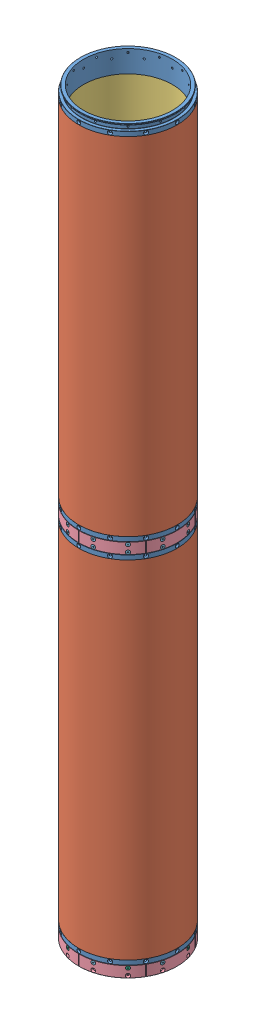
SolidWorks assembly couplingExample, configuration Default. Lengths in mm.
Overall size (235.05 1268.91 235.05).
59 component instances, 6 part files, 14 mates.
Components (placement in the parent):
- module24-1: module24 [Default] at (-49.5864 13.6661 16.8815) size (235.05 629.76 235.05)
  - moduleRing-1: moduleRing [Default] at (25.7042 -360.5051 -16.6209) size (168.91 37.68 168.91)
  - moduleRing-2: moduleRing [Default] at (25.7042 248.3364 -16.6209) x (-1 0 0) z (0 0 1) size (168.91 37.68 168.91)
  - compositeOuterSleeve-1: compositeOuterSleeve [Default] at (25.7042 -353.5986 -16.6209) x (-0.821874 0 -0.569669) z (0.569669 0 -0.821874) size (168.91 595.03 168.91)
  - compositeInnerSleeve-1: compositeInnerSleeve [Default] at (25.7042 -343.4386 -16.6209) x (0.952124 0 0.305713) z (-0.305713 0 0.952124) size (154.43 574.71 154.43)
- module24-2: module24 [Default] at (-40.5031 643.4225 -25.4436) x (0 0 1) z (-1 0 0) size (235.05 629.76 235.05)
  - moduleRing-1: moduleRing [Default] at (25.7042 -360.5051 -16.6209) size (168.91 37.68 168.91)
  - moduleRing-2: moduleRing [Default] at (25.7042 248.3364 -16.6209) x (-1 0 0) z (0 0 1) size (168.91 37.68 168.91)
  - compositeOuterSleeve-1: compositeOuterSleeve [Default] at (25.7042 -353.5986 -16.6209) x (-0.821874 0 -0.569669) z (0.569669 0 -0.821874) size (168.91 595.03 168.91)
  - compositeInnerSleeve-1: compositeInnerSleeve [Default] at (25.7042 -343.4386 -16.6209) x (0.952124 0 0.305713) z (-0.305713 0 0.952124) size (154.43 574.71 154.43)
- clampArc-1: clampArc [Default] at (-23.8822 263.0581 0.2606) x (0.866025 0 -0.500001) z (0.500001 0 0.866025) size (83.87 18.8 15.42)
- clampArc-7: clampArc [Default] at (-23.8822 -366.6983 0.2606) x (0.866025 0 -0.500001) z (0.500001 0 0.866025) size (83.87 18.8 15.42)
- 4-40x0.3125_82degCSK_flatHex_91253A107_ALLOY STEEL FLAT-HEAD SOCKET CAP SCREW-1: 4-40x0.3125_82degCSK_flatHex_91253A107_ALLOY STEEL FLAT-HEAD SOCKET CAP SCREW [91253A107] at (-45.7521 -351.5694 -81.3588) x (-0.965926 0 0.258819) z (-0.258819 0 -0.965926) size (6.48 6.48 25.61)
- 4-40x0.3125_82degCSK_flatHex_91253A107_ALLOY STEEL FLAT-HEAD SOCKET CAP SCREW-2: 4-40x0.3125_82degCSK_flatHex_91253A107_ALLOY STEEL FLAT-HEAD SOCKET CAP SCREW [91253A107] at (-66.1315 -343.8134 -72.9174) x (-0.866025 0 0.5) z (-0.5 0 -0.866025) size (6.48 6.48 25.61)
- 4-40x0.375_82degCSK_flatHex_91253A108_ALLOY STEEL FLAT-HEAD SOCKET CAP SCREW-1: 4-40x0.375_82degCSK_flatHex_91253A108_ALLOY STEEL FLAT-HEAD SOCKET CAP SCREW [91253A108] at (-83.6319 -351.5694 -59.4889) x (-0.707106 0 0.707108) z (-0.707108 0 -0.707106) size (6.48 6.48 25.62)
- 4-40x0.3125_82degCSK_flatHex_91253A107_ALLOY STEEL FLAT-HEAD SOCKET CAP SCREW-3: 4-40x0.3125_82degCSK_flatHex_91253A107_ALLOY STEEL FLAT-HEAD SOCKET CAP SCREW [91253A107] at (-45.7521 266.7331 -81.3588) x (-0.820755 0.527254 0.219921) z (-0.258819 0 -0.965926) size (6.48 6.48 25.61)
- 4-40x0.3125_82degCSK_flatHex_91253A107_ALLOY STEEL FLAT-HEAD SOCKET CAP SCREW-4: 4-40x0.3125_82degCSK_flatHex_91253A107_ALLOY STEEL FLAT-HEAD SOCKET CAP SCREW [91253A107] at (-83.6319 278.1869 -59.4889) x (-0.631584 -0.449667 0.631586) z (-0.707108 0 -0.707106) size (6.48 6.48 25.61)
- 4-40x0.3125_82degCSK_flatHex_91253A107_ALLOY STEEL FLAT-HEAD SOCKET CAP SCREW-5: 4-40x0.3125_82degCSK_flatHex_91253A107_ALLOY STEEL FLAT-HEAD SOCKET CAP SCREW [91253A107] at (-83.6319 266.7331 -59.4889) x (-0.434684 0.788732 0.434685) z (-0.707108 0 -0.707106) size (6.48 6.48 25.61)
- 4-40x0.3125_82degCSK_flatHex_91253A107_ALLOY STEEL FLAT-HEAD SOCKET CAP SCREW-6: 4-40x0.3125_82degCSK_flatHex_91253A107_ALLOY STEEL FLAT-HEAD SOCKET CAP SCREW [91253A107] at (-45.7521 278.1869 -81.3588) x (-0.965926 0 0.258819) z (-0.258819 0 -0.965926) size (6.48 6.48 25.61)
- 4-40x0.3125_82degCSK_flatHex_91253A107_ALLOY STEEL FLAT-HEAD SOCKET CAP SCREW-7: 4-40x0.3125_82degCSK_flatHex_91253A107_ALLOY STEEL FLAT-HEAD SOCKET CAP SCREW [91253A107] at (-105.5016 266.7331 22.1306) x (0.159106 0.788732 0.59379) z (-0.965926 0 0.25882) size (6.48 6.48 25.61)
- 4-40x0.3125_82degCSK_flatHex_91253A107_ALLOY STEEL FLAT-HEAD SOCKET CAP SCREW-8: 4-40x0.3125_82degCSK_flatHex_91253A107_ALLOY STEEL FLAT-HEAD SOCKET CAP SCREW [91253A107] at (-45.752 266.7331 81.8801) x (0.593791 0.788732 0.159105) z (-0.258818 0 0.965926) size (6.48 6.48 25.61)
- 4-40x0.3125_82degCSK_flatHex_91253A107_ALLOY STEEL FLAT-HEAD SOCKET CAP SCREW-9: 4-40x0.3125_82degCSK_flatHex_91253A107_ALLOY STEEL FLAT-HEAD SOCKET CAP SCREW [91253A107] at (35.8675 266.7331 60.0102) x (0.434684 0.788732 -0.434685) z (0.707108 0 0.707106) size (6.48 6.48 25.61)
- 4-40x0.3125_82degCSK_flatHex_91253A107_ALLOY STEEL FLAT-HEAD SOCKET CAP SCREW-10: 4-40x0.3125_82degCSK_flatHex_91253A107_ALLOY STEEL FLAT-HEAD SOCKET CAP SCREW [91253A107] at (57.7373 266.7331 -21.6093) x (-0.159106 0.788732 -0.59379) z (0.965926 0 -0.25882) size (6.48 6.48 25.61)
- 4-40x0.3125_82degCSK_flatHex_91253A107_ALLOY STEEL FLAT-HEAD SOCKET CAP SCREW-11: 4-40x0.3125_82degCSK_flatHex_91253A107_ALLOY STEEL FLAT-HEAD SOCKET CAP SCREW [91253A107] at (-2.0124 266.7331 -81.3589) x (-0.593791 0.788732 -0.159105) z (0.258818 0 -0.965926) size (6.48 6.48 25.61)
- 4-40x0.3125_82degCSK_flatHex_91253A107_ALLOY STEEL FLAT-HEAD SOCKET CAP SCREW-12: 4-40x0.3125_82degCSK_flatHex_91253A107_ALLOY STEEL FLAT-HEAD SOCKET CAP SCREW [91253A107] at (-105.5016 278.1869 22.1306) x (0.231177 -0.449667 0.862761) z (-0.965926 0 0.25882) size (6.48 6.48 25.61)
- 4-40x0.3125_82degCSK_flatHex_91253A107_ALLOY STEEL FLAT-HEAD SOCKET CAP SCREW-13: 4-40x0.3125_82degCSK_flatHex_91253A107_ALLOY STEEL FLAT-HEAD SOCKET CAP SCREW [91253A107] at (-45.752 278.1869 81.8801) x (0.862762 -0.449667 0.231175) z (-0.258818 0 0.965926) size (6.48 6.48 25.61)
- 4-40x0.3125_82degCSK_flatHex_91253A107_ALLOY STEEL FLAT-HEAD SOCKET CAP SCREW-14: 4-40x0.3125_82degCSK_flatHex_91253A107_ALLOY STEEL FLAT-HEAD SOCKET CAP SCREW [91253A107] at (35.8675 278.1869 60.0102) x (0.631584 -0.449667 -0.631586) z (0.707108 0 0.707106) size (6.48 6.48 25.61)
- 4-40x0.3125_82degCSK_flatHex_91253A107_ALLOY STEEL FLAT-HEAD SOCKET CAP SCREW-15: 4-40x0.3125_82degCSK_flatHex_91253A107_ALLOY STEEL FLAT-HEAD SOCKET CAP SCREW [91253A107] at (57.7373 278.1869 -21.6093) x (-0.231177 -0.449667 -0.862761) z (0.965926 0 -0.25882) size (6.48 6.48 25.61)
- 4-40x0.3125_82degCSK_flatHex_91253A107_ALLOY STEEL FLAT-HEAD SOCKET CAP SCREW-16: 4-40x0.3125_82degCSK_flatHex_91253A107_ALLOY STEEL FLAT-HEAD SOCKET CAP SCREW [91253A107] at (-2.0124 278.1869 -81.3589) x (-0.862762 -0.449667 -0.231175) z (0.258818 0 -0.965926) size (6.48 6.48 25.61)
- 4-40x0.3125_82degCSK_flatHex_91253A107_ALLOY STEEL FLAT-HEAD SOCKET CAP SCREW-17: 4-40x0.3125_82degCSK_flatHex_91253A107_ALLOY STEEL FLAT-HEAD SOCKET CAP SCREW [91253A107] at (-105.5017 266.7331 -21.6092) x (-0.219921 0.527254 0.820755) z (-0.965926 0 -0.258819) size (6.48 6.48 25.61)
- 4-40x0.3125_82degCSK_flatHex_91253A107_ALLOY STEEL FLAT-HEAD SOCKET CAP SCREW-18: 4-40x0.3125_82degCSK_flatHex_91253A107_ALLOY STEEL FLAT-HEAD SOCKET CAP SCREW [91253A107] at (-83.6318 266.7331 60.0102) x (0.600834 0.527254 0.600834) z (-0.707107 0 0.707107) size (6.48 6.48 25.61)
- 4-40x0.3125_82degCSK_flatHex_91253A107_ALLOY STEEL FLAT-HEAD SOCKET CAP SCREW-19: 4-40x0.3125_82degCSK_flatHex_91253A107_ALLOY STEEL FLAT-HEAD SOCKET CAP SCREW [91253A107] at (-2.0123 266.7331 81.8801) x (0.820755 0.527254 -0.219921) z (0.258819 0 0.965926) size (6.48 6.48 25.61)
- 4-40x0.3125_82degCSK_flatHex_91253A107_ALLOY STEEL FLAT-HEAD SOCKET CAP SCREW-20: 4-40x0.3125_82degCSK_flatHex_91253A107_ALLOY STEEL FLAT-HEAD SOCKET CAP SCREW [91253A107] at (57.7373 266.7331 22.1305) x (0.219921 0.527254 -0.820755) z (0.965926 0 0.258819) size (6.48 6.48 25.61)
- 4-40x0.3125_82degCSK_flatHex_91253A107_ALLOY STEEL FLAT-HEAD SOCKET CAP SCREW-21: 4-40x0.3125_82degCSK_flatHex_91253A107_ALLOY STEEL FLAT-HEAD SOCKET CAP SCREW [91253A107] at (35.8674 266.7331 -59.489) x (-0.600834 0.527254 -0.600834) z (0.707107 0 -0.707107) size (6.48 6.48 25.61)
- 4-40x0.3125_82degCSK_flatHex_91253A107_ALLOY STEEL FLAT-HEAD SOCKET CAP SCREW-22: 4-40x0.3125_82degCSK_flatHex_91253A107_ALLOY STEEL FLAT-HEAD SOCKET CAP SCREW [91253A107] at (-105.5017 278.1869 -21.6092) x (-0.258819 0 0.965926) z (-0.965926 0 -0.258819) size (6.48 6.48 25.61)
- 4-40x0.3125_82degCSK_flatHex_91253A107_ALLOY STEEL FLAT-HEAD SOCKET CAP SCREW-23: 4-40x0.3125_82degCSK_flatHex_91253A107_ALLOY STEEL FLAT-HEAD SOCKET CAP SCREW [91253A107] at (-83.6318 278.1869 60.0102) x (0.707107 0 0.707107) z (-0.707107 0 0.707107) size (6.48 6.48 25.61)
- 4-40x0.3125_82degCSK_flatHex_91253A107_ALLOY STEEL FLAT-HEAD SOCKET CAP SCREW-24: 4-40x0.3125_82degCSK_flatHex_91253A107_ALLOY STEEL FLAT-HEAD SOCKET CAP SCREW [91253A107] at (-2.0123 278.1869 81.8801) x (0.965926 0 -0.258819) z (0.258819 0 0.965926) size (6.48 6.48 25.61)
- 4-40x0.3125_82degCSK_flatHex_91253A107_ALLOY STEEL FLAT-HEAD SOCKET CAP SCREW-25: 4-40x0.3125_82degCSK_flatHex_91253A107_ALLOY STEEL FLAT-HEAD SOCKET CAP SCREW [91253A107] at (57.7373 278.1869 22.1305) x (0.258819 0 -0.965926) z (0.965926 0 0.258819) size (6.48 6.48 25.61)
- 4-40x0.3125_82degCSK_flatHex_91253A107_ALLOY STEEL FLAT-HEAD SOCKET CAP SCREW-26: 4-40x0.3125_82degCSK_flatHex_91253A107_ALLOY STEEL FLAT-HEAD SOCKET CAP SCREW [91253A107] at (35.8674 278.1869 -59.489) x (-0.707107 0 -0.707107) z (0.707107 0 -0.707107) size (6.48 6.48 25.61)
- clampArc-8: clampArc [Default] at (-23.8822 263.0581 0.2606) x (-0.000001 0 -1) z (1 0 -0.000001) size (83.87 18.8 15.42)
- clampArc-9: clampArc [Default] at (-23.8822 263.0581 0.2606) x (-0.866026 0 -0.499999) z (0.499999 0 -0.866026) size (83.87 18.8 15.42)
- clampArc-10: clampArc [Default] at (-23.8822 263.0581 0.2606) x (-0.866025 0 0.500001) z (-0.500001 0 -0.866025) size (83.87 18.8 15.42)
- clampArc-11: clampArc [Default] at (-23.8822 263.0581 0.2606) x (0.000001 0 1) z (-1 0 0.000001) size (83.87 18.8 15.42)
- clampArc-12: clampArc [Default] at (-23.8822 263.0581 0.2606) x (0.866026 0 0.499999) z (-0.499999 0 0.866026) size (83.87 18.8 15.42)
- 4-40x0.375_82degCSK_flatHex_91253A108_ALLOY STEEL FLAT-HEAD SOCKET CAP SCREW-2: 4-40x0.375_82degCSK_flatHex_91253A108_ALLOY STEEL FLAT-HEAD SOCKET CAP SCREW [91253A108] at (-105.5016 -351.5694 22.1306) x (0.25882 0 0.965926) z (-0.965926 0 0.25882) size (6.48 6.48 25.62)
- 4-40x0.375_82degCSK_flatHex_91253A108_ALLOY STEEL FLAT-HEAD SOCKET CAP SCREW-3: 4-40x0.375_82degCSK_flatHex_91253A108_ALLOY STEEL FLAT-HEAD SOCKET CAP SCREW [91253A108] at (-45.752 -351.5694 81.8801) x (0.965926 0 0.258818) z (-0.258818 0 0.965926) size (6.48 6.48 25.62)
- 4-40x0.375_82degCSK_flatHex_91253A108_ALLOY STEEL FLAT-HEAD SOCKET CAP SCREW-4: 4-40x0.375_82degCSK_flatHex_91253A108_ALLOY STEEL FLAT-HEAD SOCKET CAP SCREW [91253A108] at (35.8675 -351.5694 60.0102) x (0.707106 0 -0.707108) z (0.707108 0 0.707106) size (6.48 6.48 25.62)
- 4-40x0.375_82degCSK_flatHex_91253A108_ALLOY STEEL FLAT-HEAD SOCKET CAP SCREW-5: 4-40x0.375_82degCSK_flatHex_91253A108_ALLOY STEEL FLAT-HEAD SOCKET CAP SCREW [91253A108] at (57.7373 -351.5694 -21.6093) x (-0.25882 0 -0.965926) z (0.965926 0 -0.25882) size (6.48 6.48 25.62)
- 4-40x0.375_82degCSK_flatHex_91253A108_ALLOY STEEL FLAT-HEAD SOCKET CAP SCREW-6: 4-40x0.375_82degCSK_flatHex_91253A108_ALLOY STEEL FLAT-HEAD SOCKET CAP SCREW [91253A108] at (-2.0124 -351.5694 -81.3589) x (-0.965926 0 -0.258818) z (0.258818 0 -0.965926) size (6.48 6.48 25.62)
- 4-40x0.3125_82degCSK_flatHex_91253A107_ALLOY STEEL FLAT-HEAD SOCKET CAP SCREW-27: 4-40x0.3125_82degCSK_flatHex_91253A107_ALLOY STEEL FLAT-HEAD SOCKET CAP SCREW [91253A107] at (-105.5017 -351.5694 -21.6092) x (-0.258819 0 0.965926) z (-0.965926 0 -0.258819) size (6.48 6.48 25.61)
- 4-40x0.3125_82degCSK_flatHex_91253A107_ALLOY STEEL FLAT-HEAD SOCKET CAP SCREW-28: 4-40x0.3125_82degCSK_flatHex_91253A107_ALLOY STEEL FLAT-HEAD SOCKET CAP SCREW [91253A107] at (-83.6318 -351.5694 60.0102) x (0.707107 0 0.707107) z (-0.707107 0 0.707107) size (6.48 6.48 25.61)
- 4-40x0.3125_82degCSK_flatHex_91253A107_ALLOY STEEL FLAT-HEAD SOCKET CAP SCREW-29: 4-40x0.3125_82degCSK_flatHex_91253A107_ALLOY STEEL FLAT-HEAD SOCKET CAP SCREW [91253A107] at (-2.0123 -351.5694 81.8801) x (0.965926 0 -0.258819) z (0.258819 0 0.965926) size (6.48 6.48 25.61)
- 4-40x0.3125_82degCSK_flatHex_91253A107_ALLOY STEEL FLAT-HEAD SOCKET CAP SCREW-30: 4-40x0.3125_82degCSK_flatHex_91253A107_ALLOY STEEL FLAT-HEAD SOCKET CAP SCREW [91253A107] at (57.7373 -351.5694 22.1305) x (0.258819 0 -0.965926) z (0.965926 0 0.258819) size (6.48 6.48 25.61)
- 4-40x0.3125_82degCSK_flatHex_91253A107_ALLOY STEEL FLAT-HEAD SOCKET CAP SCREW-31: 4-40x0.3125_82degCSK_flatHex_91253A107_ALLOY STEEL FLAT-HEAD SOCKET CAP SCREW [91253A107] at (35.8674 -351.5694 -59.489) x (-0.707107 0 -0.707107) z (0.707107 0 -0.707107) size (6.48 6.48 25.61)
- clampArc-13: clampArc [Default] at (-23.8822 -366.6983 0.2606) x (-0.000001 0 -1) z (1 0 -0.000001) size (83.87 18.8 15.42)
- clampArc-14: clampArc [Default] at (-23.8822 -366.6983 0.2606) x (-0.866026 0 -0.499999) z (0.499999 0 -0.866026) size (83.87 18.8 15.42)
- clampArc-15: clampArc [Default] at (-23.8822 -366.6983 0.2606) x (-0.866025 0 0.500001) z (-0.500001 0 -0.866025) size (83.87 18.8 15.42)
- clampArc-16: clampArc [Default] at (-23.8822 -366.6983 0.2606) x (0.000001 0 1) z (-1 0 0.000001) size (83.87 18.8 15.42)
- clampArc-17: clampArc [Default] at (-23.8822 -366.6983 0.2606) x (0.866026 0 0.499999) z (-0.499999 0 0.866026) size (83.87 18.8 15.42)
Mates (geometry in assembly coordinates):
- Coincident2: coincident: plane of module24-1/moduleRing-2 through (-23.8822 272.46 0.2606) normal (0 1 0); plane of module24-2/moduleRing-1 through (-23.8822 272.46 0.2606) normal (0 -1 0)
- Concentric1: concentric: cylinder of module24-1/moduleRing-2 through (-23.8822 224.7083 0.2606) axis (0 -1 0) radius 76.2; cylinder of module24-2/moduleRing-1 through (-23.8822 320.2117 0.2606) axis (0 1 0) radius 76.2
- Coincident3: coincident: cone of module24-1/moduleRing-2 through (-23.8822 270.3144 0.2606) axis (0 -1 0); cone of clampArc-1 through (-23.8822 269.5037 0.2606) axis (0 -1 0)
- Coincident4: coincident: cone of module24-1/moduleRing-1 through (-23.8822 -355.1508 0.2606) axis (0 1 0); cone of clampArc-7 through (-23.8822 -355.2964 0.2606) axis (0 1 0)
- Coincident5: coincident: cone of clampArc-7 through (-45.7408 -351.5694 -81.3166) axis (0.258819 0 0.965926); cone of 4-40x0.3125_82degCSK_flatHex_91253A107_ALLOY STEEL FLAT-HEAD SOCKET CAP SCREW-1 through (-45.2064 -351.5694 -79.3225) axis (0.258819 0 0.965926)
- Parallel1: parallel: cylinder of module24-1/moduleRing-1 through (-44.3807 -351.4944 -76.2407) axis (-0.258819 0 -0.965926) radius 1.524; cylinder of clampArc-7 through (-45.7408 -351.5694 -81.3166) axis (-0.258819 0 -0.965926) radius 1.4732
- Coincident6: coincident: cone of module24-1/moduleRing-1 through (-66.1097 -343.8134 -72.8795) axis (0.5 0 0.866025); cone of 4-40x0.3125_82degCSK_flatHex_91253A107_ALLOY STEEL FLAT-HEAD SOCKET CAP SCREW-2 through (-65.0774 -343.8134 -71.0916) axis (0.5 0 0.866025)
- Coincident7: coincident: cone of clampArc-7 through (-83.601 -351.5694 -59.458) axis (0.707108 0 0.707106); cone of 4-40x0.375_82degCSK_flatHex_91253A108_ALLOY STEEL FLAT-HEAD SOCKET CAP SCREW-1 through (-82.1411 -351.5694 -57.9982) axis (0.707108 0 0.707106)
- Parallel2: parallel: cylinder of module24-1/moduleRing-2 through (-44.3807 266.6581 -76.2407) axis (-0.258819 0 -0.965926) radius 1.524; cylinder of clampArc-1 through (-45.7408 266.7331 -81.3166) axis (-0.258819 0 -0.965926) radius 1.4732
- Parallel3: parallel: cylinder of module24-2/moduleRing-1 through (-44.3807 278.2619 -76.2407) axis (-0.258819 0 -0.965926) radius 1.524; cylinder of clampArc-1 through (-45.7408 278.1869 -81.3166) axis (-0.258819 0 -0.965926) radius 1.4732
- Coincident8: coincident: cone of clampArc-1 through (-45.7408 266.7331 -81.3166) axis (0.258819 0 0.965926); cone of 4-40x0.3125_82degCSK_flatHex_91253A107_ALLOY STEEL FLAT-HEAD SOCKET CAP SCREW-3 through (-45.2064 266.7331 -79.3225) axis (0.258819 0 0.965926)
- Coincident9: coincident: cone of clampArc-1 through (-45.7408 278.1869 -81.3166) axis (0.258819 0 0.965926); cone of 4-40x0.3125_82degCSK_flatHex_91253A107_ALLOY STEEL FLAT-HEAD SOCKET CAP SCREW-6 through (-45.2064 278.1869 -79.3225) axis (0.258819 0 0.965926)
- Coincident10: coincident: cone of clampArc-1 through (-83.601 278.1869 -59.458) axis (0.707108 0 0.707106); cone of 4-40x0.3125_82degCSK_flatHex_91253A107_ALLOY STEEL FLAT-HEAD SOCKET CAP SCREW-4 through (-82.1411 278.1869 -57.9982) axis (0.707108 0 0.707106)
- Coincident11: coincident: cone of clampArc-1 through (-83.601 266.7331 -59.458) axis (0.707108 0 0.707106); cone of 4-40x0.3125_82degCSK_flatHex_91253A107_ALLOY STEEL FLAT-HEAD SOCKET CAP SCREW-5 through (-82.1411 266.7331 -57.9982) axis (0.707108 0 0.707106)
